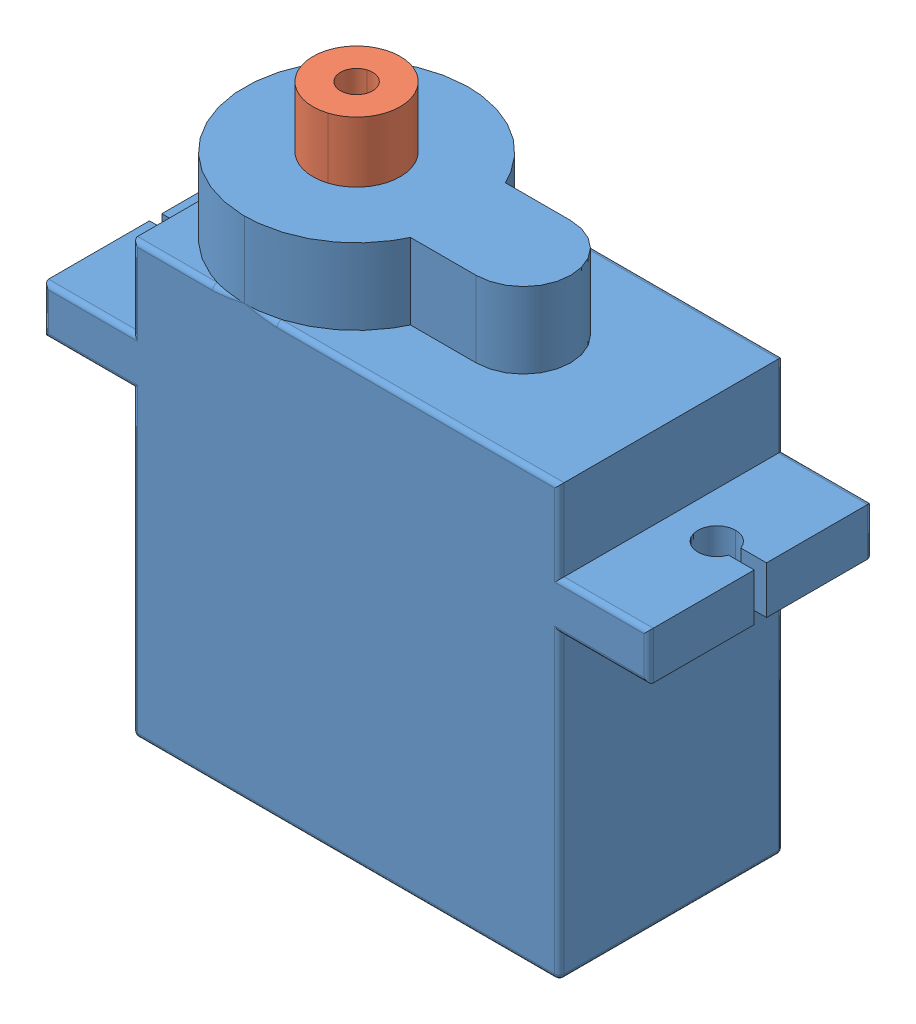
SolidWorks assembly sg90 micro servo.STEP, configuration Default. Lengths in mm.
Overall size (31.9 29.9 11.81).
2 component instances, 2 part files, 0 mates.
Components (placement in the parent):
- Part1.STEP-1: Part1.STEP [Default] at (11.25 -26.7 0) size (31.9 26.7 11.81)
- axis.step.STEP-1: axis.step.STEP [Default] at (5.9 3.2 5.9) x (0.296886 0 0.954913) z (0 -1 0) size (4.6 4.6 7.2)
